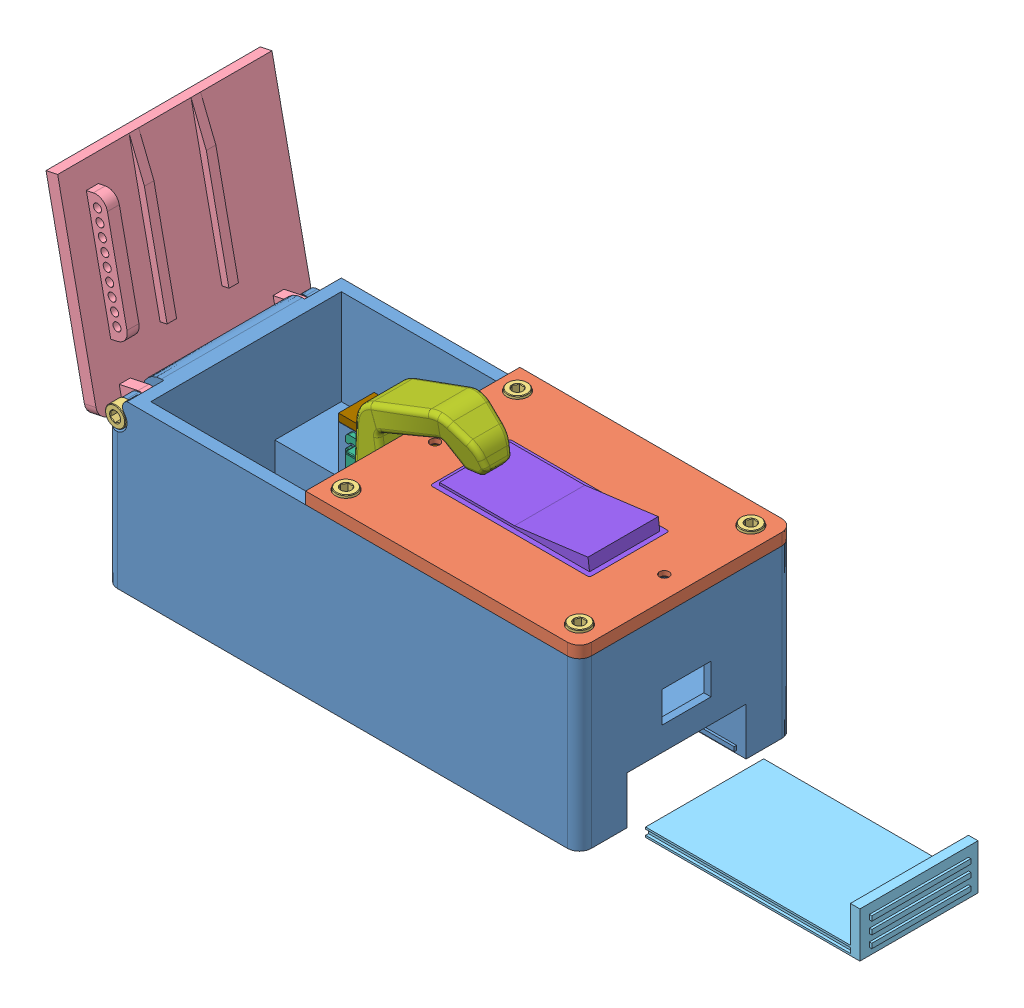
SolidWorks assembly Full Assembly, configuration Default. Lengths in mm.
Overall size (322.41 140.53 90.87).
13 component instances, 9 part files, 28 mates.
Components (placement in the parent):
- Box-1: Box [Default] at origin size (199 70 90.64)
- Switch Lid-1: Switch Lid [Default] at (37.5 65 0) size (115 5 90)
- 91290A201_Black-Oxide Alloy Steel Socket Head Screw-1: 91290A201_Black-Oxide Alloy Steel Socket Head Screw [91290A201] at (-12 33.5 36) x (1 0 0) z (0 1 0) size (8.5 8.5 75.67)
- 91290A201_Black-Oxide Alloy Steel Socket Head Screw-2: 91290A201_Black-Oxide Alloy Steel Socket Head Screw [91290A201] at (86 33.5 -36) x (1 0 0) z (0 1 0) size (8.5 8.5 75.67)
- 91290A201_Black-Oxide Alloy Steel Socket Head Screw-3: 91290A201_Black-Oxide Alloy Steel Socket Head Screw [91290A201] at (86 33.5 36) x (1 0 0) z (0 1 0) size (8.5 8.5 75.67)
- 91290A201_Black-Oxide Alloy Steel Socket Head Screw-4: 91290A201_Black-Oxide Alloy Steel Socket Head Screw [91290A201] at (-12 33.5 -36) x (1 0 0) z (0 1 0) size (8.5 8.5 75.67)
- Moving Lid-1: Moving Lid [Default] at (-115.5677 92.2553 0) x (-0.205254 0.978709 0) z (0 0 1) size (83.4 17 90)
- battery lid-1: battery lid [Default] at (147.3915 -5 -0.2) size (91 19 49.6)
- 91290A201_Black-Oxide Alloy Steel Socket Head Screw-5: 91290A201_Black-Oxide Alloy Steel Socket Head Screw [91290A201] at (-100 57 7.5) x (0.900818 0.434197 0) z (0 0 1) size (8.5 8.5 75.67)
- MG995.step-1: MG995.step [Default] at (-31.3 35 -39) size (55.5 20 44.5)
- arm-1: arm [Default] at (-27.428 51.392 -9.5) x (0.936685 0.350174 0) z (0.350174 -0.936685 0) size (60.31 20.24 55)
- switch mockup-1: switch mockup [Default] at (37.5 65 0) size (67 10 33.5)
- servo hold down-2: servo hold down [Default] at (-31.65 45.1647 -19.6) size (63.3 3 15)
Mates (geometry in assembly coordinates):
- Coincident1: coordinate: point of Box-1
- Coincident2: coincident anti-aligned: plane of Box-1 through (0 65 0) normal (0 1 0); plane of Switch Lid-1 through (37.5 65 0) normal (0 -1 0)
- Coincident3: coincident aligned: plane of Box-1 through (-95 65 45) normal (0 0 1); plane of Switch Lid-1 through (37.5 70 45) normal (0 0 1)
- Coincident4: coincident aligned: plane of Box-1 through (95 65 45) normal (1 0 0); plane of Switch Lid-1 through (95 70 0) normal (1 0 0)
- Concentric1: concentric anti-aligned: cylinder of Switch Lid-1 through (-12 70 36) axis (0 1 0) radius 4.5; cylinder of 91290A201_Black-Oxide Alloy Steel Socket Head Screw-1 through (-12 -4 36) axis (0 -1 0) radius 4.25
- Concentric2: concentric anti-aligned: cylinder of Switch Lid-1 through (-12 70 -36) axis (0 1 0) radius 4.5; cylinder of 91290A201_Black-Oxide Alloy Steel Socket Head Screw-4 through (-12 -4 -36) axis (0 -1 0) radius 4.25
- Concentric3: concentric anti-aligned: cylinder of Switch Lid-1 through (86 70 -36) axis (0 1 0) radius 4.5; cylinder of 91290A201_Black-Oxide Alloy Steel Socket Head Screw-2 through (86 -4 -36) axis (0 -1 0) radius 4.25
- Concentric4: concentric anti-aligned: cylinder of Switch Lid-1 through (86 70 36) axis (0 1 0) radius 4.5; cylinder of 91290A201_Black-Oxide Alloy Steel Socket Head Screw-3 through (86 -4 36) axis (0 -1 0) radius 4.25
- Coincident6: coincident anti-aligned: plane of Switch Lid-1 through (88.75 66 36) normal (0 1 0); plane of 91290A201_Black-Oxide Alloy Steel Socket Head Screw-3 through (82 66 36) normal (0 -1 0)
- Coincident7: coincident anti-aligned: plane of Switch Lid-1 through (88.75 66 -36) normal (0 1 0); plane of 91290A201_Black-Oxide Alloy Steel Socket Head Screw-2 through (82 66 -36) normal (0 -1 0)
- Coincident8: coincident anti-aligned: plane of Switch Lid-1 through (-9.25 66 -36) normal (0 1 0); plane of 91290A201_Black-Oxide Alloy Steel Socket Head Screw-4 through (-16 66 -36) normal (0 -1 0)
- Coincident9: coincident anti-aligned: plane of Switch Lid-1 through (-9.25 66 36) normal (0 1 0); plane of 91290A201_Black-Oxide Alloy Steel Socket Head Screw-1 through (-16 66 36) normal (0 -1 0)
- Coincident10: coincident aligned: plane of Box-1 through (-95 65 45) normal (0 0 1); plane of Moving Lid-1 through (-111.9022 50.4169 45) normal (0 0 1)
- Coincident12: coincident aligned: plane of Box-1 through (0 -5 0) normal (0 -1 0); plane of battery lid-1 through (147.3915 -5 -0.2) normal (0 -1 0)
- Coincident13: coincident anti-aligned: plane of Box-1 through (5 15 -25) normal (0 0 1); plane of battery lid-1 through (102.3915 -1.2 -25) normal (0 0 -1)
- Concentric7: concentric anti-aligned: cylinder of MG995.step-1 through (-21.3 35 0) axis (0 0 -1) radius 6; cylinder of arm-1 through (-21.3 35 10.5) axis (0 0 1) radius 2.75
- Coincident16: coincident anti-aligned: plane of MG995.step-1 through (-21.3 35 0.5) normal (0 0 1); plane of arm-1 through (-27.428 51.392 0.5) normal (0 0 -1)
- Coincident17: coincident: plane of Box-1 through (0 45 -39) normal (0 0 1); plane of MG995.step-1 through (-31.3 35 -39) normal (0 0 -1)
- Coincident18: coincident anti-aligned: plane of Box-1 through (-51.3 45 0) normal (1 0 0); plane of MG995.step-1 through (-51.3 45 -3) normal (-1 0 0)
- Coincident19: coincident anti-aligned: plane of Box-1 through (0 25 0) normal (0 1 0); plane of MG995.step-1 through (-51.3 25 -3) normal (0 -1 0)
- Concentric8: concentric aligned: cylinder of Box-1 through (-100 57 35) axis (0 0 1) radius 2.75; cylinder of Moving Lid-1 through (-100 57 25) axis (0 0 1) radius 2.75
- Concentric9: concentric anti-aligned: cylinder of Box-1 through (-100 57 35) axis (0 0 1) radius 2.75; cylinder of 91290A201_Black-Oxide Alloy Steel Socket Head Screw-5 through (-100 57 -30) axis (0 0 -1) radius 4.25
- Coincident25: coincident anti-aligned: plane of Box-1 through (0 0 40) normal (0 0 1); plane of 91290A201_Black-Oxide Alloy Steel Socket Head Screw-5 through (-103.6033 55.2632 40) normal (0 0 -1)
- Coincident26: coincident anti-aligned: plane of Switch Lid-1 through (37.5 70 16.75) normal (0 0 -1); plane of switch mockup-1 through (4 70 16.75) normal (0 0 1)
- Coincident27: coincident anti-aligned: plane of Switch Lid-1 through (4 70 0) normal (1 0 0); plane of switch mockup-1 through (4 70 16.75) normal (-1 0 0)
- Coincident28: coincident aligned: plane of Switch Lid-1 through (37.5 70 0) normal (0 1 0); plane of switch mockup-1 through (37.5 70 0) normal (0 1 0)
- Coincident29: coincident aligned: plane of Box-1 through (-63.3 45 0) normal (-1 0 0); plane of servo hold down-2 through (-63.3 48.1647 -12.1) normal (-1 0 0)
- Coincident30: coincident aligned: plane of Box-1 through (0 45 -12.1) normal (0 0 1); plane of servo hold down-2 through (-63.3 48.1647 -12.1) normal (0 0 1)
